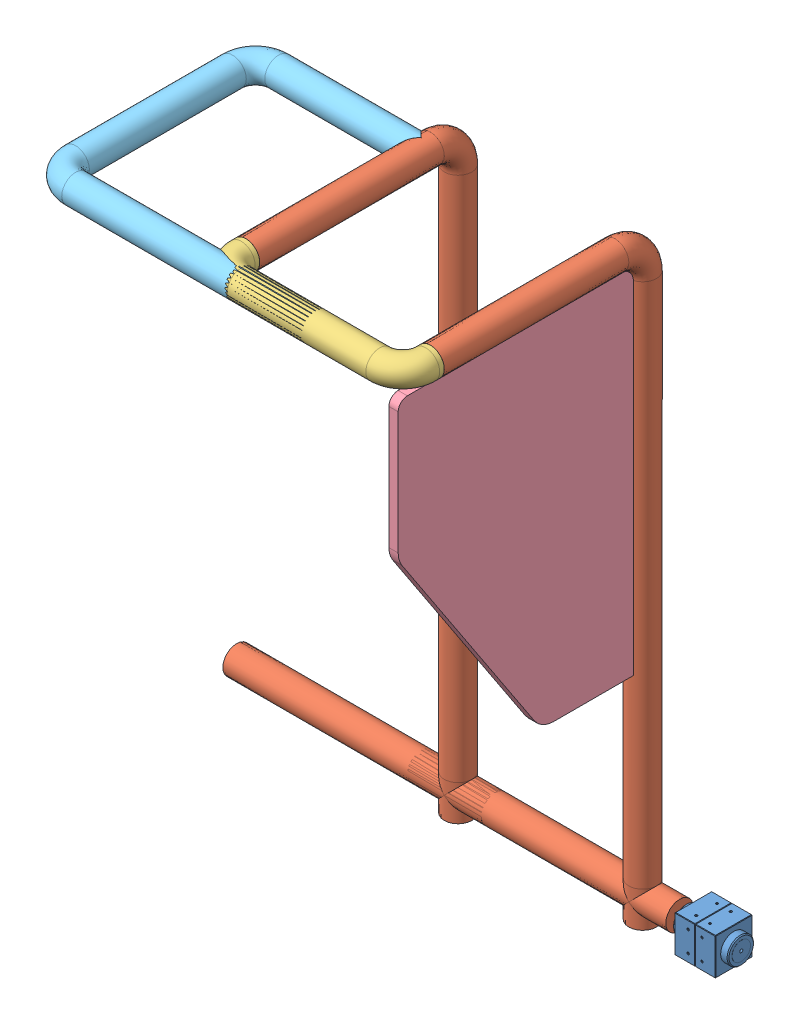
SolidWorks assembly half_seat_right, configuration Default. Lengths in mm.
Overall size (546.87 653.61 325.4).
6 component instances, 5 part files, 8 mates.
Components (placement in the parent):
- LINOS-FI-1030-35C_bulk-1: LINOS-FI-1030-35C_bulk [Default] at (36.7653 23.6083 41.7735) size (60.2 40 40)
- Part10^half_seat_right-1: Part10^half_seat_right [Default] at origin size (280 653.61 245) (virtual)
- Part11^half_seat_right-1: Part11^half_seat_right [Default] at (0 1077.2167 63.5471) x (1 0 0) z (0 0 -1) size (230 30 45) (virtual)
- Part10^half_seat_right-2: Part10^half_seat_right [Default] at (-200 0 0) size (280 653.61 245) (virtual)
- Part12^half_seat_right-1: Part12^half_seat_right [Default] at (-75 200 83.5471) x (-1 0 0) z (0 0 -1) size (24 385 320.4) (virtual)
- Part13^half_seat_right-1: Part13^half_seat_right [Default] at (0.4566 1077.2167 63.5471) x (1 0 0) z (0 0 -1) size (300 30 250) (virtual)
Mates (geometry in assembly coordinates):
- Coincident6: coincident aligned: plane of Part10^half_seat_right-1 through (-40 0 41.7735) normal (0 -1 0); plane of Part10^half_seat_right-2 through (-240 0 41.7735) normal (0 -1 0)
- Concentric1: concentric anti-aligned: cylinder of Part11^half_seat_right-1 through (-65 638.6083 301.7735) axis (-1 0 0) radius 15; cylinder of Part13^half_seat_right-1 through (-384.5434 638.6083 301.7735) axis (1 0 0) radius 15
- Parallel1: parallel aligned: cylinder of Part10^half_seat_right-2 through (-240 638.6083 71.7735) axis (0 0 -1) radius 15; cylinder of Part13^half_seat_right-1 through (-419.5434 638.6083 276.7735) axis (0 0 -1) radius 15
- Coincident7: coincident anti-aligned: plane of Part12^half_seat_right-1 through (-45 608.6083 71.7735) normal (-1 0 0)
- Tangent2: tangent anti-aligned: cylinder of Part10^half_seat_right-1 through (-40 38.6083 41.7735) axis (0 1 0) radius 15; plane of Part12^half_seat_right-1 through (-45 238.6083 56.7735) normal (0 0 -1)
- Tangent3: tangent anti-aligned: cylinder of Part10^half_seat_right-1 through (-40 638.6083 71.7735) axis (0 0 1) radius 15; plane of Part12^half_seat_right-1 through (-45 623.6083 71.7735) normal (0 1 0)
- Coincident8: coincident anti-aligned: circle of Part10^half_seat_right-2; circle of Part11^half_seat_right-1
- Coincident9: coincident aligned: circle of Part10^half_seat_right-1; circle of Part11^half_seat_right-1
